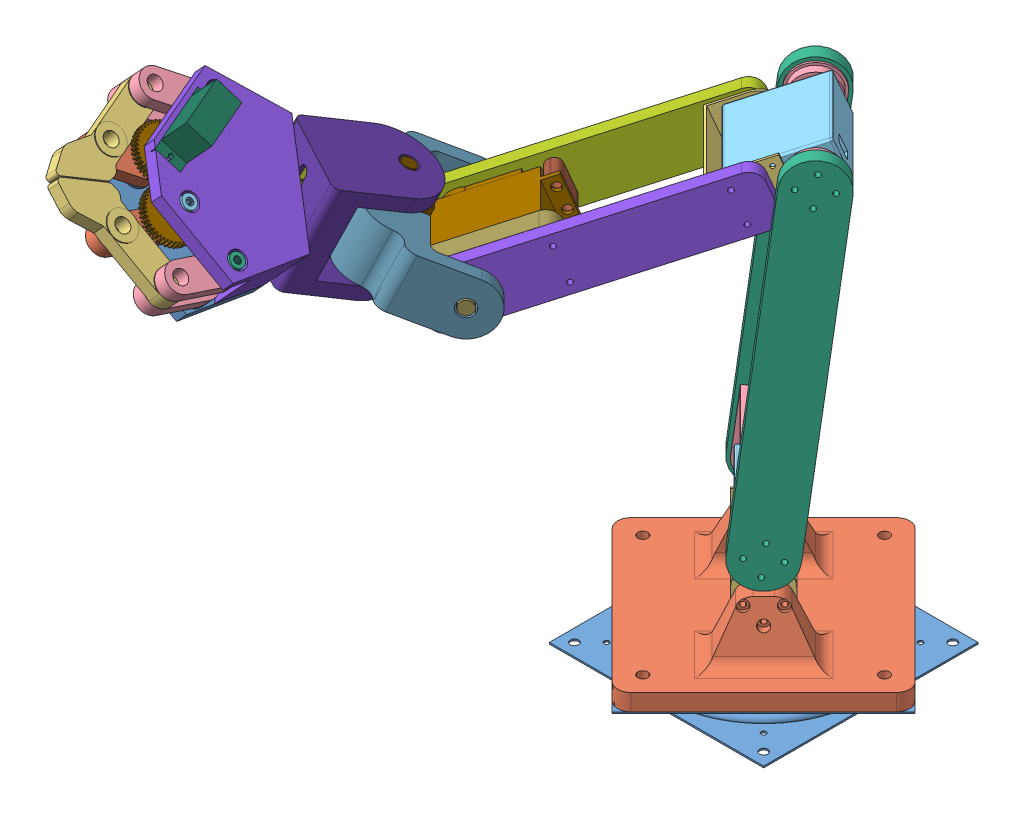
SolidWorks assembly Arm_Assy, configuration Default. Lengths in mm.
Overall size (249.01 270.64 299.75).
45 component instances, 27 part files, 65 mates.
Components (placement in the parent):
- 6031K170_CORROSION-RESISTANT TURNTABLE-1: 6031K170_CORROSION-RESISTANT TURNTABLE [6031K17] at (63.5864 72.5493 107.2084) size (143.68 8.13 143.68)
- Base_Top_Plate-1: Base_Top_Plate [Default] at (-8.2556 75.8513 107.2084) x (0.707107 0 0.707107) z (-0.707107 0 0.707107) size (101.6 33.34 101.6)
- Motor_Mounting_Bracket_(Small)-1: Motor_Mounting_Bracket_(Small) [Default] at (70.8829 90.1388 130.2203) x (-0.707107 0 -0.707107) z (0.707107 0 -0.707107) size (42.86 26.99 22.23)
- Motor_Mounting_Bracket_(Large)-1: Motor_Mounting_Bracket_(Large) [Default] at (93.1312 153.137 116.5368) x (-0.707107 0 -0.707107) z (-0.702504 0.113909 0.702504) size (53.98 39.69 22.23)
- LDX218_Servo-1: LDX218_Servo [Default] at (70.9212 96.0138 128.6853) x (-0.707107 0 -0.707107) z (0.707107 0 -0.707107) size (53.75 40 20)
- Bottom_Arm_Link-1: Bottom_Arm_Link [Default] at (93.6507 201.7178 124.9976) x (0.702504 -0.113909 -0.702504) z (-0.707107 0 -0.707107) size (25.4 177.8 6.35)
- Bottom_Arm_Link-2: Bottom_Arm_Link [Default] at (46.5044 201.7178 77.8512) x (0.702504 -0.113909 -0.702504) z (0.707107 0 0.707107) size (25.4 177.8 6.35)
- Motor_Mounting_Bracket_(Small)-2: Motor_Mounting_Bracket_(Small) [Default] at (40.6565 253.9971 101.2441) x (0.707107 0 0.707107) z (-0.257747 0.9312 0.257747) size (42.86 26.99 22.23)
- Motor_Mounting_Bracket_(Large)-2: Motor_Mounting_Bracket_(Large) [Default] at (62.6371 247.767 70.6988) x (0.707107 0 0.707107) z (-0.702504 0.113909 0.702504) size (53.98 39.69 22.23)
- LDX218_Servo-2: LDX218_Servo [Default] at (44.9865 257.1745 98.4108) x (0.707107 0 0.707107) z (-0.257747 0.9312 0.257747) size (53.75 40 20)
- Forearm_1-1: Forearm_1 [Default] at (48.1078 283.6938 93.7928) x (0.257747 -0.9312 -0.257747) z (-0.707107 0 -0.707107) size (25.4 127 6.35)
- Forearm_2-1: Forearm_2 [Default] at (84.963 260.0414 117.5544) x (-0.257747 0.9312 0.257747) z (0.707107 0 0.707107) size (25.4 127 6.35)
- MG996R_Servo-1: MG996R_Servo [Default] at (24.5403 251.5533 173.9289) x (-0.658458 -0.364509 0.658458) z (0.257747 -0.9312 -0.257747) size (54 46 19)
- MG996R_Motor_Mounting_Disc-1: MG996R_Motor_Mounting_Disc [Default] at (-27.0352 231.5893 157.6221) x (-0.543182 -0.640239 0.543182) z (0.707107 0 0.707107) size (20 20 5)
- Mounting_Spacer-1: Mounting_Spacer [Default] at (-23.7183 236.9729 178.3469) x (-0.658458 -0.364509 0.658458) z (0.257747 -0.9312 -0.257747) size (7 9 19)
- Mounting_Spacer-2: Mounting_Spacer [Default] at (-3.744 251.5533 145.6446) x (0.658458 0.364509 -0.658458) z (0.257747 -0.9312 -0.257747) size (7 9 19)
- Motor_Coupler_for_Forearm-1: Motor_Coupler_for_Forearm [Default] at (36.8432 233.4277 165.5858) x (-0.658458 -0.364509 0.658458) z (0.257747 -0.9312 -0.257747) size (53.98 23.81 25.4)
- Washer_5-16ID_5-8OD_1-16T-1: Washer_5-16ID_5-8OD_1-16T [Default] at (13.4202 231.5894 198.0774) x (0.707107 0 -0.707107) z (0.707107 0 0.707107) size (15.88 15.88 1.59)
- Wrist_Joint_1(Lower Wrist Joint)-1: Wrist_Joint_1(Lower Wrist Joint) [Default] at (23.3903 214.7421 199.2443) x (-0.707107 0 -0.707107) z (0.295719 0.908351 -0.295719) size (71.44 57.15 25.4)
- Micro_Servo-1: Micro_Servo [Default] at (-22.7008 258.326 203.1653) x (-0.707107 0 -0.707107) z (-0.642301 0.418209 0.642301) size (31.9 29.9 11.8)
- Micro_Servo_Blade-1: Micro_Servo_Blade [Default] at (-31.9251 228.6989 204.0458) x (0.321657 -0.386169 -0.864529) z (-0.295719 -0.908351 0.295719) size (7 32 3.75)
- Wrist_Joint_2(Middle_Wrist_Joint)-1: Wrist_Joint_2(Middle_Wrist_Joint) [Default] at (-62.7498 242.0647 230.6771) x (0.899493 -0.160537 0.406375) z (0.295719 0.908351 -0.295719) size (38.1 50.8 46.04)
- Micro_Servo_Coupler_for_Middle_Joint-1: Micro_Servo_Coupler_for_Middle_Joint [Default] at (-8.0133 251.0923 193.6043) x (-0.707107 0 -0.707107) z (0.642301 -0.418209 -0.642301) size (19.05 10.69 25.4)
- Claw_Assy-1: Claw_Assy [Default] at (-74.2515 174.159 238.2905) x (-0.665446 0.557342 -0.49654) z (0.673587 0.735013 -0.077702) size (94.99 96.36 51.62)
  - claw_palm-1: claw_palm [Default] at (27.676 20.1757 68.2758) size (78.64 57.15 7.94)
  - claw_link1-1: claw_link1 [Default] at (38.7885 66.1431 76.2133) x (0.20498 0.978766 0) z (0 0 1) size (31.75 12.7 6.35)
  - claw_link1-2: claw_link1 [Default] at (16.5635 66.1431 76.2133) x (-0.259293 0.965799 0) z (0 0 1) size (31.75 12.7 6.35)
  - claw_claw-1: claw_claw [Default] at (62.9336 59.5157 89.3101) x (-0.766044 0.642788 0) z (0 0 -1) size (58.06 20.17 7.14)
  - claw_claw-2: claw_claw [Default] at (-8.6163 59.2687 82.9601) x (0.766044 0.642788 0) z (0 0 1) size (58.06 20.17 7.14)
  - claw_link2(Not Drive)-1: claw_link2(Not Drive) [Default] at (-7.8336 68.2148 76.2133) x (0.259293 -0.965799 0) z (0 0 1) size (31.75 12.7 6.35)
  - claw_link2(Not Drive)-2: claw_link2(Not Drive) [Default] at (58.246 49.8163 76.2133) x (0.20498 0.978766 0) z (0 0 1) size (31.75 12.7 6.35)
  - Drive_Shaft-1: Drive_Shaft [Default] at (16.5635 66.1431 68.2758) x (0.039244 0.99923 0) z (0.99923 -0.039244 0) size (6.35 35.73 6.35)
  - Drive_Shaft-2: Drive_Shaft [Default] at (38.7885 66.1431 68.2758) x (0.712352 -0.701822 0) z (-0.701822 -0.712352 0) size (6.35 35.73 6.35)
  - Driven_Shaft-1: Driven_Shaft [Default] at (-2.894 49.8163 68.2758) x (-0.621237 0.783623 0) z (0.783623 0.621237 0) size (6.35 35.73 6.35)
  - Driven_Shaft-2: Driven_Shaft [Default] at (58.246 49.8163 68.2758) x (1 0 0) z (0 -1 0) size (6.35 35.73 6.35)
  - claw_link2(Not Drive)-3: claw_link2(Not Drive) [Default] at (-7.8336 68.2148 89.707) x (0.259293 -0.965799 0) z (0 0 1) size (31.75 12.7 6.35)
  - claw_link2(Not Drive)-4: claw_link2(Not Drive) [Default] at (58.246 49.8163 89.707) x (0.20498 0.978766 0) z (0 0 1) size (31.75 12.7 6.35)
  - claw_link_spacer-1: claw_link_spacer [Default] at (-2.894 49.8163 89.707) x (-0.57859 -0.815619 0) z (0.815619 -0.57859 0) size (7.94 7.14 7.94)
  - claw_link_spacer-2: claw_link_spacer [Default] at (58.246 49.8163 89.707) x (1 0 0) z (0 1 0) size (7.94 7.14 7.94)
  - claw_palm_top-1: claw_palm_top [Default] at (27.676 20.1757 97.6445) size (78.64 57.15 29.37)
  - Micro_Servo-1: Micro_Servo [Default] at (38.0613 74.4552 119.8945) x (0.766044 -0.642788 0) z (0.642788 0.766044 0) size (31.9 29.9 11.8)
  - Micro_Servo-2: Micro_Servo [Default] at (33.426 44.3415 93.3258) x (-1 0 0) z (0 0 1) size (31.9 29.9 11.8)
  - 57655K220_PLASTIC GEAR--14-.5 DEG PRESSURE ANGLE-1: 57655K220_PLASTIC GEAR--14-.5 DEG PRESSURE ANGLE [57655K22] at (16.5635 66.1431 93.1945) x (0.979587 -0.201023 0) z (0 0 1) size (23.14 23.14 9.54)
  - 57655K220_PLASTIC GEAR--14-.5 DEG PRESSURE ANGLE-2: 57655K220_PLASTIC GEAR--14-.5 DEG PRESSURE ANGLE [57655K22] at (38.7885 66.1431 93.1945) x (0.995 -0.099874 0) z (0 0 1) size (23.14 23.14 9.54)
- Micro_Servo_Blade-2: Micro_Servo_Blade [Default] at (-38.3249 259.3363 230.3147) x (0.899493 -0.160537 0.406375) z (0.321657 -0.386169 -0.864529) size (7 32 3.75)
Mates (geometry in assembly coordinates):
- Concentric1: concentric anti-aligned: cylinder of Base_Top_Plate-1 through (89.8269 99.0138 133.4489) axis (-0.707107 0 -0.707107) radius 1.1906; cylinder of Motor_Mounting_Bracket_(Small)-1 through (69.9922 99.0138 113.6142) axis (0.707107 0 0.707107) radius 1
- Concentric3: concentric anti-aligned: cylinder of Base_Top_Plate-1 through (84.8771 106.0138 138.3986) axis (-0.707107 0 -0.707107) radius 1.1906; cylinder of Motor_Mounting_Bracket_(Small)-1 through (65.0425 106.0138 118.564) axis (0.707107 0 0.707107) radius 1
- Coincident1: coincident anti-aligned: plane of 6031K170_CORROSION-RESISTANT TURNTABLE-1 through (110.0137 75.8513 107.2084) normal (0 1 0); plane of Base_Top_Plate-1 through (-8.2556 75.8513 107.2084) normal (0 -1 0)
- Coincident7: coincident aligned: plane of 6031K170_CORROSION-RESISTANT TURNTABLE-1 through (63.5864 -128.0853 35.3664) normal (-0.707107 0 -0.707107); plane of Base_Top_Plate-1 through (-8.2556 83.7888 107.2084) normal (-0.707107 0 -0.707107)
- Width1: width aligned: plane of Motor_Mounting_Bracket_(Small)-1 through (56.2899 90.1388 84.1965) normal (-0.707107 0 -0.707107); plane of Motor_Mounting_Bracket_(Small)-1 through (86.5983 117.1263 114.5049) normal (0.707107 0 0.707107); plane of Base_Top_Plate-1 through (42.8196 75.8513 158.2836) normal (-0.707107 0 -0.707107); plane of Base_Top_Plate-1 through (12.5112 75.8513 127.9752) normal (0.707107 0 0.707107)
- Concentric8: concentric aligned: cylinder of Motor_Mounting_Bracket_(Large)-1 through (91.023 126.0138 134.645) axis (-0.707107 0 -0.707107) radius 4; cylinder of LDX218_Servo-1 through (82.942 126.0138 126.564) axis (-0.707107 0 -0.707107) radius 4
- Width2: width anti-aligned: plane of LDX218_Servo-1 through (82.942 126.0138 126.564) normal (0.707107 0 0.707107); plane of LDX218_Servo-1 through (44.9379 126.0138 88.5599) normal (-0.707107 0 -0.707107); plane of Motor_Mounting_Bracket_(Large)-1 through (39.3519 155.6686 93.9839) normal (-0.707107 0 -0.707107); plane of Motor_Mounting_Bracket_(Large)-1 through (74.3214 116.2394 135.3466) normal (0.707107 0 0.707107)
- Concentric11: concentric aligned: cylinder of Motor_Mounting_Bracket_(Small)-1 through (51.8773 98.5138 106.1059) axis (-0.707107 0 -0.707107) radius 1; cylinder of LDX218_Servo-1 through (47.4128 98.5138 101.6414) axis (-0.707107 0 -0.707107) radius 1
- Concentric12: concentric aligned: cylinder of Motor_Mounting_Bracket_(Small)-1 through (62.4839 98.5138 95.4993) axis (-0.707107 0 -0.707107) radius 1; cylinder of LDX218_Servo-1 through (58.0194 98.5138 91.0348) axis (-0.707107 0 -0.707107) radius 1
- Width3: width anti-aligned: plane of LDX218_Servo-1 through (56.2516 96.0138 85.7315) normal (-0.707107 0 -0.707107); plane of LDX218_Servo-1 through (85.0633 96.0138 114.5432) normal (0.707107 0 0.707107); plane of Motor_Mounting_Bracket_(Small)-1 through (57.0383 117.1263 84.9448) normal (0.707107 0 0.707107); plane of Motor_Mounting_Bracket_(Small)-1 through (85.85 91.1971 113.7565) normal (-0.707107 0 -0.707107)
- Coincident4: coincident anti-aligned: plane of Motor_Mounting_Bracket_(Large)-1 through (39.3519 155.6686 93.9839) normal (-0.707107 0 -0.707107); plane of Bottom_Arm_Link-2 through (44.8569 126.0138 88.4789) normal (0.707107 0 0.707107)
- Concentric13: concentric anti-aligned: cylinder of Motor_Mounting_Bracket_(Large)-1 through (91.5868 132.9682 134.0812) axis (-0.707107 0 -0.707107) radius 1; cylinder of Bottom_Arm_Link-2 through (38.5494 132.9682 81.0437) axis (0.707107 0 0.707107) radius 1.1906
- Concentric14: concentric anti-aligned: cylinder of Motor_Mounting_Bracket_(Large)-1 through (90.4592 119.0593 135.2088) axis (-0.707107 0 -0.707107) radius 1; cylinder of Bottom_Arm_Link-2 through (37.4217 119.0593 82.1714) axis (0.707107 0 0.707107) radius 1.1906
- Coincident5: coincident anti-aligned: plane of Motor_Mounting_Bracket_(Large)-1 through (74.3214 116.2394 135.3466) normal (0.707107 0 0.707107); plane of Bottom_Arm_Link-1 through (95.2982 277.4218 114.3698) normal (-0.707107 0 -0.707107)
- Concentric15: concentric aligned: cylinder of Motor_Mounting_Bracket_(Large)-1 through (90.4592 119.0593 135.2088) axis (-0.707107 0 -0.707107) radius 1; cylinder of Bottom_Arm_Link-1 through (89.3306 119.0593 134.0802) axis (-0.707107 0 -0.707107) radius 1.1906
- Concentric16: concentric aligned: cylinder of Motor_Mounting_Bracket_(Large)-1 through (91.5868 132.9682 134.0812) axis (-0.707107 0 -0.707107) radius 1; cylinder of Bottom_Arm_Link-1 through (90.4582 132.9682 132.9526) axis (-0.707107 0 -0.707107) radius 1.1906
- Coincident6: coincident anti-aligned: plane of Bottom_Arm_Link-2 through (44.8569 126.0138 88.4789) normal (0.707107 0 0.707107); plane of Motor_Mounting_Bracket_(Large)-2 through (50.2205 289.7278 83.1153) normal (-0.707107 0 -0.707107)
- Concentric21: concentric aligned: cylinder of Bottom_Arm_Link-2 through (50.8245 284.3763 68.7686) axis (0.707107 0 0.707107) radius 1.1906; cylinder of Motor_Mounting_Bracket_(Large)-2 through (49.6959 284.3763 67.6399) axis (0.707107 0 0.707107) radius 1
- Concentric22: concentric aligned: cylinder of Bottom_Arm_Link-2 through (49.6969 270.4674 69.8962) axis (0.707107 0 0.707107) radius 1.1906; cylinder of Motor_Mounting_Bracket_(Large)-2 through (48.5682 270.4674 68.7676) axis (0.707107 0 0.707107) radius 1
- Concentric23: concentric aligned: cylinder of Motor_Mounting_Bracket_(Large)-2 through (49.1321 277.4218 68.2038) axis (0.707107 0 0.707107) radius 4; cylinder of LDX218_Servo-2 through (57.2131 277.4218 76.2848) axis (0.707107 0 0.707107) radius 4
- Width5: width anti-aligned: plane of LDX218_Servo-2 through (57.2131 277.4218 76.2848) normal (-0.707107 0 -0.707107); plane of LDX218_Servo-2 through (95.2172 277.4218 114.2889) normal (0.707107 0 0.707107); plane of Motor_Mounting_Bracket_(Large)-2 through (60.7088 277.4218 79.7805) normal (0.707107 0 0.707107); plane of Motor_Mounting_Bracket_(Large)-2 through (91.7214 277.4218 110.7931) normal (-0.707107 0 -0.707107)
- Concentric24: concentric aligned: cylinder of Motor_Mounting_Bracket_(Small)-2 through (72.8107 279.8494 112.21) axis (0.707107 0 0.707107) radius 1; cylinder of LDX218_Servo-2 through (77.2752 279.8494 116.6745) axis (0.707107 0 0.707107) radius 1
- Concentric25: concentric aligned: cylinder of Motor_Mounting_Bracket_(Small)-2 through (66.8 260.4138 118.2207) axis (0.707107 0 0.707107) radius 1; cylinder of LDX218_Servo-2 through (71.2645 260.4138 122.6852) axis (0.707107 0 0.707107) radius 1
- Width6: width anti-aligned: plane of LDX218_Servo-2 through (68.6433 275.7985 132.3774) normal (0.707107 0 0.707107); plane of LDX218_Servo-2 through (39.8316 275.7985 103.5657) normal (-0.707107 0 -0.707107); plane of Motor_Mounting_Bracket_(Small)-2 through (82.2582 284.5302 118.7624) normal (-0.707107 0 -0.707107); plane of Motor_Mounting_Bracket_(Small)-2 through (36.3733 275.0788 107.024) normal (0.707107 0 0.707107)
- Coincident8: coincident aligned: plane of 6031K170_CORROSION-RESISTANT TURNTABLE-1 through (-8.2556 -128.0853 107.2084) normal (-0.707107 0 0.707107); plane of Base_Top_Plate-1 through (-8.2556 83.7888 107.2084) normal (-0.707107 0 0.707107)
- Coincident9: coincident anti-aligned: plane of Motor_Mounting_Bracket_(Small)-2 through (52.6982 284.5302 89.2024) normal (-0.707107 0 -0.707107); plane of Forearm_1-1 through (48.1078 283.6938 93.7928) normal (0.707107 0 0.707107)
- Concentric26: concentric aligned: cylinder of Forearm_1-1 through (52.4308 263.6132 94.2323) axis (-0.707107 0 -0.707107) radius 1.1906; cylinder of Motor_Mounting_Bracket_(Small)-2 through (58.7979 263.6132 100.5995) axis (-0.707107 0 -0.707107) radius 1
- Concentric27: concentric aligned: cylinder of Forearm_1-1 through (48.8223 276.65 97.8408) axis (-0.707107 0 -0.707107) radius 1.1906; cylinder of Motor_Mounting_Bracket_(Small)-2 through (55.1895 276.65 104.2079) axis (-0.707107 0 -0.707107) radius 1
- Coincident10: coincident anti-aligned: plane of Motor_Mounting_Bracket_(Small)-2 through (65.2365 274.693 137.2809) normal (0.707107 0 0.707107); plane of Forearm_2-1 through (84.963 260.0414 117.5544) normal (-0.707107 0 -0.707107)
- Concentric30: concentric aligned: cylinder of Motor_Mounting_Bracket_(Small)-2 through (66.8 260.4138 118.2207) axis (0.707107 0 0.707107) radius 1; cylinder of Forearm_2-1 through (73.1671 260.4138 124.5878) axis (0.707107 0 0.707107) radius 1.1906
- Concentric31: concentric aligned: cylinder of Motor_Mounting_Bracket_(Small)-2 through (62.9338 274.3818 122.0869) axis (0.707107 0 0.707107) radius 1; cylinder of Forearm_2-1 through (69.3009 274.3818 128.454) axis (0.707107 0 0.707107) radius 1.1906
- Coincident11: coincident anti-aligned: plane of MG996R_Servo-1 through (-25.621 231.5893 159.0364) normal (-0.707107 0 -0.707107); plane of MG996R_Motor_Mounting_Disc-1 through (-25.621 231.5893 159.0364) normal (0.707107 0 0.707107)
- Concentric32: concentric anti-aligned: cylinder of MG996R_Servo-1 through (-25.621 231.5893 159.0364) axis (0.707107 0 0.707107) radius 3; cylinder of MG996R_Motor_Mounting_Disc-1 through (-23.4997 231.5893 161.1577) axis (-0.707107 0 -0.707107) radius 3
- Coincident12: coincident anti-aligned: plane of Forearm_1-1 through (48.1078 283.6938 93.7928) normal (0.707107 0 0.707107); plane of MG996R_Servo-1 through (-8.5796 238.6745 150.4802) normal (-0.707107 0 -0.707107)
- Width8: width aligned: plane of MG996R_Servo-1 through (29.4375 233.8605 169.0317) normal (0.257747 -0.9312 -0.257747); plane of MG996R_Servo-1 through (24.5403 251.5533 173.9289) normal (-0.257747 0.9312 0.257747); plane of Forearm_1-1 through (50.1645 260.0414 82.7559) normal (0.257747 -0.9312 -0.257747); plane of Forearm_1-1 through (43.6177 283.6938 89.3027) normal (-0.257747 0.9312 0.257747)
- Coincident13: coincident aligned: plane of Forearm_1-1 through (-40.0064 237.4012 172.9268) normal (-0.658458 -0.364509 0.658458); plane of MG996R_Servo-1 through (-23.4303 216.7285 178.0589) normal (-0.658458 -0.364509 0.658458)
- Concentric33: concentric aligned: cylinder of Mounting_Spacer-1 through (-21.2235 231.3245 183.7896) axis (-0.707107 0 -0.707107) radius 1.9844; cylinder of MG996R_Servo-1 through (-19.6781 231.3245 185.3351) axis (-0.707107 0 -0.707107) radius 2.05
- Concentric34: concentric aligned: cylinder of MG996R_Servo-1 through (-17.1006 222.0125 182.7576) axis (-0.707107 0 -0.707107) radius 2.05; cylinder of Mounting_Spacer-1 through (-18.6461 222.0125 181.2122) axis (-0.707107 0 -0.707107) radius 1.9844
- Width9: width aligned: plane of Mounting_Spacer-1 through (-18.8211 219.2801 173.4497) normal (0.707107 0 0.707107); plane of Mounting_Spacer-1 through (-25.1851 219.2801 167.0857) normal (-0.707107 0 -0.707107); plane of Forearm_1-1 through (48.1078 283.6938 93.7928) normal (0.707107 0 0.707107); plane of MG996R_Servo-1 through (2.62 251.5533 152.0086) normal (-0.707107 0 -0.707107)
- Concentric35: concentric anti-aligned: cylinder of MG996R_Servo-1 through (14.5054 239.5089 151.1516) axis (-0.707107 0 -0.707107) radius 2.05; cylinder of Mounting_Spacer-2 through (-1.3416 239.5089 135.3047) axis (0.707107 0 0.707107) radius 1.9844
- Concentric36: concentric anti-aligned: cylinder of MG996R_Servo-1 through (11.9279 248.8209 153.7291) axis (-0.707107 0 -0.707107) radius 2.05; cylinder of Mounting_Spacer-2 through (-3.919 248.8209 137.8822) axis (0.707107 0 0.707107) radius 1.9844
- Width10: width anti-aligned: plane of Mounting_Spacer-2 through (7.5172 233.8605 147.1114) normal (0.707107 0 0.707107); plane of Mounting_Spacer-2 through (1.1532 233.8605 140.7474) normal (-0.707107 0 -0.707107); plane of MG996R_Servo-1 through (2.62 251.5533 152.0086) normal (-0.707107 0 -0.707107); plane of Forearm_1-1 through (48.1078 283.6938 93.7928) normal (0.707107 0 0.707107)
- Coincident14: coincident anti-aligned: plane of MG996R_Servo-1 through (29.4375 233.8605 169.0317) normal (0.707107 0 0.707107); plane of Motor_Coupler_for_Forearm-1 through (34.8633 233.4277 163.6059) normal (-0.707107 0 -0.707107)
- Concentric37: concentric aligned: axis of Forearm_1-1 through (-21.3783 231.5894 163.2789) axis (-0.707107 0 -0.707107); cylinder of Motor_Coupler_for_Forearm-1 through (18.9887 231.5894 203.6459) axis (-0.707107 0 -0.707107) radius 3.175
- Parallel1: parallel aligned: plane of MG996R_Servo-1 through (3.0992 219.2801 195.37) normal (-0.658458 -0.364509 0.658458); plane of Motor_Coupler_for_Forearm-1 through (-5.4322 213.7533 194.3908) normal (-0.658458 -0.364509 0.658458)
- Concentric38: concentric aligned: cylinder of Motor_Coupler_for_Forearm-1 through (18.9887 231.5894 203.6459) axis (-0.707107 0 -0.707107) radius 3.175; cylinder of Washer_5-16ID_5-8OD_1-16T-1 through (14.5427 231.5894 199.2) axis (-0.707107 0 -0.707107) radius 3.9688
- Coincident15: coincident anti-aligned: plane of Forearm_2-1 through (89.4531 260.0414 122.0445) normal (0.707107 0 0.707107); plane of Washer_5-16ID_5-8OD_1-16T-1 through (13.4202 231.5894 198.0774) normal (-0.707107 0 -0.707107)
- Concentric39: concentric anti-aligned: cylinder of Motor_Coupler_for_Forearm-1 through (18.9887 231.5894 203.6459) axis (-0.707107 0 -0.707107) radius 3.175; cylinder of Wrist_Joint_1(Lower Wrist Joint)-1 through (6.5611 231.5894 191.2183) axis (0.707107 0 0.707107) radius 3.9688
- Coincident16: coincident anti-aligned: plane of MG996R_Motor_Mounting_Disc-1 through (-27.0352 231.5893 157.6221) normal (-0.707107 0 -0.707107); plane of Wrist_Joint_1(Lower Wrist Joint)-1 through (-15.1223 237.8142 145.7092) normal (0.707107 0 0.707107)
- Parallel2: parallel anti-aligned: plane of Wrist_Joint_1(Lower Wrist Joint)-1 through (-46.289 238.0208 192.9538) normal (0.642301 -0.418209 -0.642301); plane of Micro_Servo-1 through (-29.4136 237.7064 209.8781) normal (-0.642301 0.418209 0.642301)
- Coincident18: coincident anti-aligned: plane of Wrist_Joint_1(Lower Wrist Joint)-1 through (25.2829 220.5555 197.3517) normal (0.295719 0.908351 -0.295719); plane of Micro_Servo-1 through (-28.142 241.6123 208.6065) normal (-0.295719 -0.908351 0.295719)
- Coincident19: coincident anti-aligned: plane of Micro_Servo-1 through (-31.9251 228.6989 204.0458) normal (-0.295719 -0.908351 0.295719); plane of Micro_Servo_Blade-1 through (-31.9251 228.6989 204.0458) normal (0.295719 0.908351 -0.295719)
- Concentric41: concentric anti-aligned: cylinder of Micro_Servo-1 through (-31.9251 228.6989 204.0458) axis (0.295719 0.908351 -0.295719) radius 2.3; cylinder of Micro_Servo_Blade-1 through (-31.2598 230.7427 203.3804) axis (-0.295719 -0.908351 0.295719) radius 2.5
- Concentric42: concentric anti-aligned: cylinder of Wrist_Joint_1(Lower Wrist Joint)-1 through (-22.9057 256.4036 195.0264) axis (-0.295719 -0.908351 0.295719) radius 6; cylinder of Micro_Servo-1 through (-30.9788 231.6056 203.0995) axis (0.295719 0.908351 -0.295719) radius 5.9
- Concentric43: concentric anti-aligned: cylinder of Micro_Servo_Blade-1 through (-22.0623 228.2978 207.8945) axis (-0.295719 -0.908351 0.295719) radius 0.5; cylinder of Wrist_Joint_2(Middle_Wrist_Joint)-1 through (-25.3784 218.1116 211.2107) axis (0.295719 0.908351 -0.295719) radius 1
- Concentric44: concentric anti-aligned: cylinder of Micro_Servo_Blade-1 through (-40.9516 231.6691 199.3606) axis (-0.295719 -0.908351 0.295719) radius 0.5; cylinder of Wrist_Joint_2(Middle_Wrist_Joint)-1 through (-44.2678 221.4829 202.6768) axis (0.295719 0.908351 -0.295719) radius 1
- Coincident21: coincident anti-aligned: plane of Micro_Servo_Blade-1 through (-32.3687 227.3363 204.4893) normal (-0.295719 -0.908351 0.295719); plane of Wrist_Joint_2(Middle_Wrist_Joint)-1 through (-45.4114 229.6641 198.5969) normal (0.295719 0.908351 -0.295719)
- Concentric49: concentric aligned: cylinder of Wrist_Joint_1(Lower Wrist Joint)-1 through (-25.0336 240.8841 188.1739) axis (0.295719 0.908351 -0.295719) radius 0.7937; cylinder of Micro_Servo_Coupler_for_Middle_Joint-1 through (-21.9418 250.3808 185.0822) axis (0.295719 0.908351 -0.295719) radius 0.7937
- Concentric50: concentric aligned: cylinder of Wrist_Joint_1(Lower Wrist Joint)-1 through (-28.2891 248.851 209.39) axis (0.295719 0.908351 -0.295719) radius 0.7937; cylinder of Micro_Servo_Coupler_for_Middle_Joint-1 through (-25.1974 258.3477 206.2983) axis (0.295719 0.908351 -0.295719) radius 0.7937
- Coincident22: coincident anti-aligned: plane of Wrist_Joint_1(Lower Wrist Joint)-1 through (30.9015 237.8142 191.733) normal (0.295719 0.908351 -0.295719); plane of Micro_Servo_Coupler_for_Middle_Joint-1 through (-8.0133 251.0923 193.6043) normal (-0.295719 -0.908351 0.295719)
- Concentric51: concentric anti-aligned: cylinder of Claw_Assy-1/Micro_Servo-2 through (-38.3249 259.3363 230.3147) axis (-0.321657 0.386169 0.864529) radius 2.3; cylinder of Micro_Servo_Blade-2 through (-39.0487 260.2051 232.2599) axis (0.321657 -0.386169 -0.864529) radius 2.5
- Coincident23: coincident anti-aligned: plane of Claw_Assy-1/Micro_Servo-2 through (-38.3249 259.3363 230.3147) normal (0.321657 -0.386169 -0.864529); plane of Micro_Servo_Blade-2 through (-38.3249 259.3363 230.3147) normal (-0.321657 0.386169 0.864529)
- Concentric52: concentric aligned: cylinder of Wrist_Joint_2(Middle_Wrist_Joint)-1 through (-33.1303 253.0997 216.3528) axis (-0.321657 0.386169 0.864529) radius 1.75; cylinder of Micro_Servo_Blade-2 through (-37.8425 258.757 229.0179) axis (-0.321657 0.386169 0.864529) radius 1.25
- Concentric53: concentric anti-aligned: cylinder of Wrist_Joint_2(Middle_Wrist_Joint)-1 through (-30.0252 262.6374 213.2477) axis (-0.321657 0.386169 0.864529) radius 1; cylinder of Micro_Servo_Blade-2 through (-35.6748 269.4201 228.4323) axis (0.321657 -0.386169 -0.864529) radius 0.5
- Coincident24: coincident anti-aligned: plane of Wrist_Joint_2(Middle_Wrist_Joint)-1 through (-37.8425 258.757 229.0179) normal (-0.321657 0.386169 0.864529); plane of Micro_Servo_Blade-2 through (-37.8425 258.757 229.0179) normal (0.321657 -0.386169 -0.864529)
